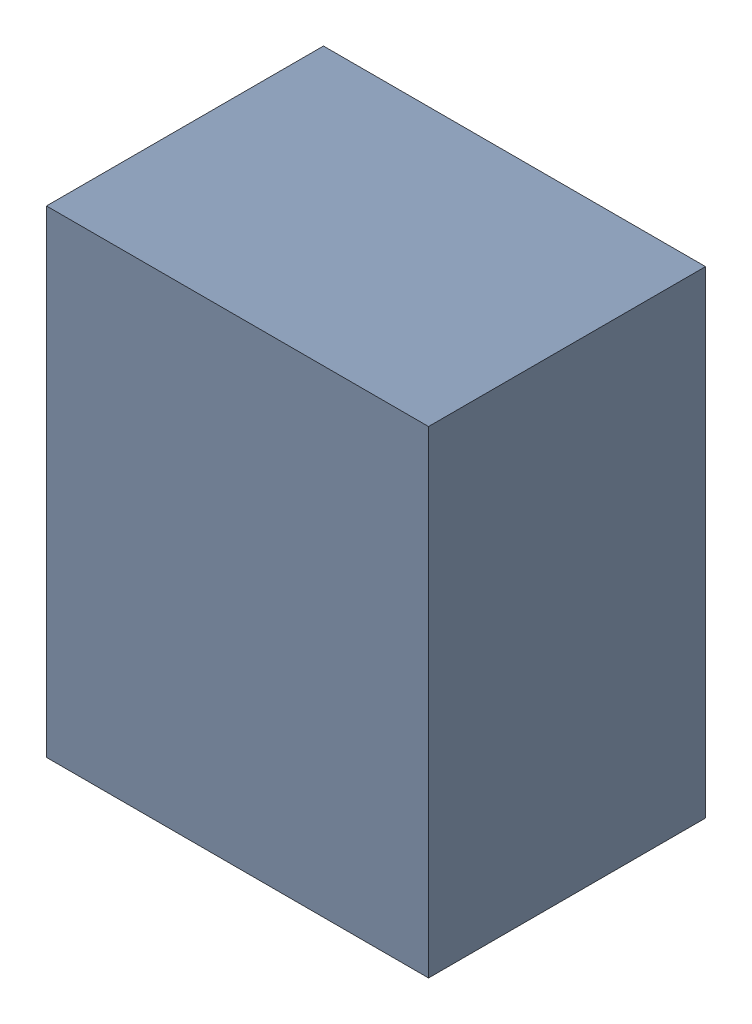
SolidWorks assembly U30, configuration Default. Lengths in mm.
Overall size (0.8 1 0.58).
2 component instances, 1 part files, 0 mates.
Components (placement in the parent):
- 836751984-1: 836751984 [Default] at (133.05 72.15 0.5) size (0.8 1 0.58)
  - Extruded_32-1: Extruded_32 [Default] at origin size (0.8 1 0.58)
